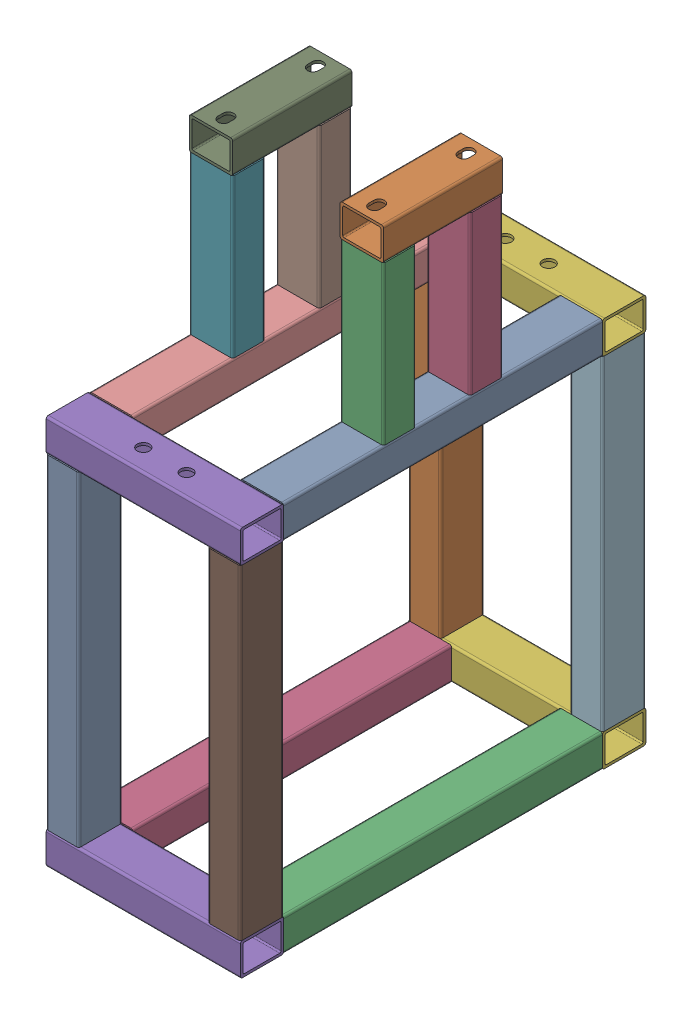
SolidWorks assembly Stand Assembly, configuration Default. Lengths in mm.
Overall size (227.56 680.52 475.21).
18 component instances, 6 part files, 51 mates.
Components (placement in the parent):
- Stand - Long Horizontal-1: Stand - Long Horizontal [6527K991] at (159.8005 177.7296 100.9544) size (50.8 38.1 373.61)
- Stand - Bearing Base-1: Stand - Bearing Base [6527K991] at (159.8005 401.049 217.9113) size (50.8 38.1 139.7)
- Stand - Bearing Leg-1: Stand - Bearing Leg [6527K991] at (159.8005 196.7796 338.5613) x (1 0 0) z (0 1 0) size (50.8 38.1 185.22)
- Stand - Bearing Leg-2: Stand - Bearing Leg [6527K991] at (159.8005 196.7796 236.9613) x (1 0 0) z (0 1 0) size (50.8 38.1 185.22)
- Stand - Short Horizontal - Holes-1: Stand - Short Horizontal - Holes [6527K991] at (-42.3632 177.7296 499.9681) x (0 0 -1) z (1 0 0) size (50.8 38.1 227.56)
- Stand - Short Horizontal - Holes-2: Stand - Short Horizontal - Holes [6527K991] at (185.2005 177.7296 75.5544) x (0 0 1) z (-1 0 0) size (50.8 38.1 227.56)
- Stand - Bearing Leg-3: Stand - Bearing Leg [6527K991] at (-16.9632 381.999 338.5613) x (1 0 0) z (0 -1 0) size (50.8 38.1 185.22)
- Stand - Bearing Leg-4: Stand - Bearing Leg [6527K991] at (-16.9632 381.999 236.9613) x (1 0 0) z (0 -1 0) size (50.8 38.1 185.22)
- Stand - Bearing Base-2: Stand - Bearing Base [6527K991] at (-16.9632 401.049 217.9113) size (50.8 38.1 139.7)
- Stand - Long Horizontal-2: Stand - Long Horizontal [6527K991] at (-16.9632 177.7296 100.9544) size (50.8 38.1 373.61)
- Stand - Legs-1: Stand - Legs [6527K991] at (166.1505 -222.3204 499.9681) x (0 0 -1) z (0 1 0) size (50.8 38.1 381)
- Stand - Legs-2: Stand - Legs [6527K991] at (166.1505 158.6796 75.5544) x (0 0 1) z (0 -1 0) size (50.8 38.1 381)
- Stand - Legs-3: Stand - Legs [6527K991] at (-23.3132 158.6796 499.9681) x (0 0 -1) z (0 -1 0) size (50.8 38.1 381)
- Stand - Legs-4: Stand - Legs [6527K991] at (-23.3132 -222.3204 75.5544) x (0 0 -1) z (0 1 0) size (50.8 38.1 381)
- Stand - Long Horizontal-3: Stand - Long Horizontal [6527K991] at (159.8005 -241.3704 100.9544) size (50.8 38.1 373.61)
- Stand - Long Horizontal-4: Stand - Long Horizontal [6527K991] at (-16.9632 -241.3704 100.9544) size (50.8 38.1 373.61)
- Stand - Short Horizontal-1: Stand - Short Horizontal [6527K991] at (185.2005 -241.3704 499.9681) x (0 0 1) z (-1 0 0) size (50.8 38.1 227.56)
- Stand - Short Horizontal-2: Stand - Short Horizontal [6527K991] at (-42.3632 -241.3704 75.5544) x (0 0 -1) z (1 0 0) size (50.8 38.1 227.56)
Mates (geometry in assembly coordinates):
- Coincident1: coincident anti-aligned: plane of Stand Assembly - 1.5 by 2 inch bearing horizontal-1 through (182.6605 381.999 357.6113) normal (0 -1 0); plane of Stand Assembly - 1.5 by 2 inch bearing vertical-2 through (182.6605 381.999 253.4713) normal (0 1 0)
- Coincident2: coincident anti-aligned: plane of Stand Assembly - 1.5 by 2 inch bearing horizontal-1 through (182.6605 381.999 357.6113) normal (0 -1 0); plane of Stand Assembly - 1.5 by 2 inch bearing vertical-1 through (182.6605 381.999 355.0713) normal (0 1 0)
- Coincident3: coincident aligned: line of Stand Assembly - 1.5 by 2 inch bearing horizontal-1 through (136.9405 381.999 357.6113) axis (1 0 0); line of Stand Assembly - 1.5 by 2 inch bearing vertical-1 through (136.9405 381.999 357.6113) axis (1 0 0)
- Coincident4: coincident anti-aligned: line of Stand Assembly - 1.5 by 2 inch bearing horizontal-1 through (136.9405 381.999 217.9113) axis (1 0 0); line of Stand Assembly - 1.5 by 2 inch bearing vertical-2 through (182.6605 381.999 217.9113) axis (-1 0 0)
- Coincident5: coincident aligned: plane of Stand Assembly - 1.5 by 2 inch bearing horizontal-1 through (185.2005 384.539 357.6113) normal (1 0 0); plane of Stand Assembly - 1.5 by 2 inch bearing vertical-2 through (185.2005 381.999 253.4713) normal (1 0 0)
- Coincident6: coincident aligned: plane of Stand Assembly - 1.5 by 2 inch bearing horizontal-1 through (185.2005 384.539 357.6113) normal (1 0 0); plane of Stand Assembly - 1.5 by 2 inch bearing vertical-1 through (185.2005 381.999 355.0713) normal (1 0 0)
- Coincident7: coincident anti-aligned: plane of Stand Assembly - 1.5 by 2 inch-1 through (182.6605 196.7796 474.5681) normal (0 1 0); plane of Stand Assembly - 1.5 by 2 inch bearing vertical-2 through (182.6605 196.7796 253.4713) normal (0 -1 0)
- Coincident8: coincident anti-aligned: line of Stand Assembly - 1.5 by 2 inch-1 through (136.9405 196.7796 217.9113) axis (1 0 0); line of Stand Assembly - 1.5 by 2 inch bearing vertical-2 through (182.6605 196.7796 217.9113) axis (-1 0 0)
- Coincident9: coincident aligned: plane of Stand Assembly - 1.5 by 2 inch-1 through (185.2005 161.2196 474.5681) normal (1 0 0); plane of Stand Assembly - 1.5 by 2 inch bearing vertical-2 through (185.2005 381.999 253.4713) normal (1 0 0)
- Coincident10: coincident anti-aligned: plane of Stand Assembly - 1.5 by 2 inch-1 through (182.6605 161.2196 100.9544) normal (0 0 -1); plane of Stand Assembly - 1.5 by 2 inch side piece-2 through (-42.3632 161.2196 100.9544) normal (0 0 1)
- Coincident11: coincident aligned: plane of Stand Assembly - 1.5 by 2 inch-1 through (185.2005 161.2196 474.5681) normal (1 0 0); plane of Stand Assembly - 1.5 by 2 inch side piece-2 through (185.2005 161.2196 98.4144) normal (1 0 0)
- Coincident12: coincident aligned: plane of Stand Assembly - 1.5 by 2 inch-1 through (182.6605 196.7796 474.5681) normal (0 1 0); plane of Stand Assembly - 1.5 by 2 inch side piece-2 through (-42.3632 196.7796 98.4144) normal (0 1 0)
- Coincident13: coincident anti-aligned: plane of Stand Assembly - 1.5 by 2 inch-1 through (182.6605 161.2196 474.5681) normal (0 0 1); plane of Stand Assembly - 1.5 by 2 inch side piece-1 through (185.2005 161.2196 474.5681) normal (0 0 -1)
- Coincident14: coincident aligned: plane of Stand Assembly - 1.5 by 2 inch-1 through (185.2005 161.2196 474.5681) normal (1 0 0); plane of Stand Assembly - 1.5 by 2 inch side piece-1 through (185.2005 161.2196 477.1081) normal (1 0 0)
- Coincident15: coincident aligned: plane of Stand Assembly - 1.5 by 2 inch-1 through (182.6605 196.7796 474.5681) normal (0 1 0); plane of Stand Assembly - 1.5 by 2 inch side piece-1 through (185.2005 196.7796 477.1081) normal (0 1 0)
- Coincident19: coincident anti-aligned: plane of Stand Assembly - 1.5 by 2 inch side piece-2 through (-42.3632 161.2196 100.9544) normal (0 0 1); plane of Stand Assembly - 1.5 by 2 inch-2 through (5.8968 161.2196 100.9544) normal (0 0 -1)
- Coincident20: coincident aligned: plane of Stand Assembly - 1.5 by 2 inch side piece-2 through (-42.3632 161.2196 98.4144) normal (-1 0 0); plane of Stand Assembly - 1.5 by 2 inch-2 through (-42.3632 161.2196 474.5681) normal (-1 0 0)
- Coincident21: coincident aligned: plane of Stand Assembly - 1.5 by 2 inch side piece-2 through (-42.3632 196.7796 98.4144) normal (0 1 0); plane of Stand Assembly - 1.5 by 2 inch-2 through (5.8968 196.7796 474.5681) normal (0 1 0)
- Coincident22: coincident anti-aligned: plane of Stand Assembly - 1.5 by 2 inch bearing vertical-4 through (5.8968 381.999 220.4513) normal (0 1 0); plane of Stand Assembly - 1.5 by 2 inch bearing horizontal-2 through (5.8968 381.999 357.6113) normal (0 -1 0)
- Coincident23: coincident anti-aligned: plane of Stand Assembly - 1.5 by 2 inch bearing vertical-3 through (5.8968 381.999 322.0513) normal (0 1 0); plane of Stand Assembly - 1.5 by 2 inch bearing horizontal-2 through (5.8968 381.999 357.6113) normal (0 -1 0)
- Coincident24: coincident aligned: line of Stand Assembly - 1.5 by 2 inch bearing vertical-4 through (-39.8232 381.999 217.9113) axis (1 0 0); line of Stand Assembly - 1.5 by 2 inch bearing horizontal-2 through (-39.8232 381.999 217.9113) axis (1 0 0)
- Coincident25: coincident aligned: plane of Stand Assembly - 1.5 by 2 inch bearing vertical-4 through (-42.3632 196.7796 220.4513) normal (-1 0 0); plane of Stand Assembly - 1.5 by 2 inch bearing horizontal-2 through (-42.3632 384.539 357.6113) normal (-1 0 0)
- Coincident26: coincident anti-aligned: line of Stand Assembly - 1.5 by 2 inch bearing vertical-3 through (5.8968 381.999 357.6113) axis (-1 0 0); line of Stand Assembly - 1.5 by 2 inch bearing horizontal-2 through (-39.8232 381.999 357.6113) axis (1 0 0)
- Coincident27: coincident aligned: plane of Stand Assembly - 1.5 by 2 inch bearing vertical-3 through (-42.3632 196.7796 322.0513) normal (-1 0 0); plane of Stand Assembly - 1.5 by 2 inch bearing horizontal-2 through (-42.3632 384.539 357.6113) normal (-1 0 0)
- Coincident28: coincident anti-aligned: plane of Stand Assembly - 1.5 by 2 inch bearing vertical-3 through (5.8968 196.7796 322.0513) normal (0 -1 0); plane of Stand Assembly - 1.5 by 2 inch-2 through (5.8968 196.7796 474.5681) normal (0 1 0)
- Coincident29: coincident aligned: plane of Stand Assembly - 1.5 by 2 inch bearing vertical-3 through (-42.3632 196.7796 322.0513) normal (-1 0 0); plane of Stand Assembly - 1.5 by 2 inch-2 through (-42.3632 161.2196 474.5681) normal (-1 0 0)
- Coincident30: coincident anti-aligned: line of Stand Assembly - 1.5 by 2 inch bearing vertical-3 through (5.8968 196.7796 357.6113) axis (-1 0 0); line of Stand Assembly - 1.5 by 2 inch-2 through (-39.8232 196.7796 357.6113) axis (1 0 0)
- Coincident33: coincident anti-aligned: plane of Stand Assembly - 1.5 by 2 inch side piece-2 through (-42.3632 158.6796 98.4144) normal (0 -1 0); plane of Stand Assembly - 1.5 by 2 inch legs-4 through (-6.8032 158.6796 52.6944) normal (0 1 0)
- Coincident34: coincident anti-aligned: plane of Stand Assembly - 1.5 by 2 inch side piece-2 through (-42.3632 158.6796 98.4144) normal (0 -1 0); plane of Stand Assembly - 1.5 by 2 inch legs-2 through (182.6605 158.6796 98.4144) normal (0 1 0)
- Coincident37: coincident aligned: plane of Stand Assembly - 1.5 by 2 inch side piece-2 through (185.2005 161.2196 98.4144) normal (1 0 0); plane of Stand Assembly - 1.5 by 2 inch legs-2 through (185.2005 -222.3204 98.4144) normal (1 0 0)
- Coincident38: coincident aligned: plane of Stand Assembly - 1.5 by 2 inch side piece-2 through (-42.3632 161.2196 50.1544) normal (0 0 -1); plane of Stand Assembly - 1.5 by 2 inch legs-2 through (182.6605 -222.3204 50.1544) normal (0 0 -1)
- Coincident39: coincident aligned: plane of Stand Assembly - 1.5 by 2 inch side piece-2 through (-42.3632 161.2196 98.4144) normal (-1 0 0); plane of Stand Assembly - 1.5 by 2 inch legs-4 through (-42.3632 158.6796 52.6944) normal (-1 0 0)
- Coincident40: coincident aligned: plane of Stand Assembly - 1.5 by 2 inch side piece-2 through (-42.3632 161.2196 50.1544) normal (0 0 -1); plane of Stand Assembly - 1.5 by 2 inch legs-4 through (-6.8032 158.6796 50.1544) normal (0 0 -1)
- Coincident41: coincident anti-aligned: plane of Stand Assembly - 1.5 by 2 inch side piece-1 through (185.2005 158.6796 477.1081) normal (0 -1 0); plane of Stand Assembly - 1.5 by 2 inch legs-3 through (-39.8232 158.6796 477.1081) normal (0 1 0)
- Coincident42: coincident aligned: plane of Stand Assembly - 1.5 by 2 inch side piece-1 through (-42.3632 161.2196 477.1081) normal (-1 0 0); plane of Stand Assembly - 1.5 by 2 inch legs-3 through (-42.3632 -222.3204 477.1081) normal (-1 0 0)
- Coincident43: coincident aligned: plane of Stand Assembly - 1.5 by 2 inch side piece-1 through (185.2005 161.2196 525.3681) normal (0 0 1); plane of Stand Assembly - 1.5 by 2 inch legs-3 through (-39.8232 -222.3204 525.3681) normal (0 0 1)
- Coincident44: coincident anti-aligned: plane of Stand Assembly - 1.5 by 2 inch side piece-1 through (185.2005 158.6796 477.1081) normal (0 -1 0); plane of Stand Assembly - 1.5 by 2 inch legs-1 through (182.6605 158.6796 477.1081) normal (0 1 0)
- Coincident45: coincident aligned: plane of Stand Assembly - 1.5 by 2 inch side piece-1 through (185.2005 161.2196 477.1081) normal (1 0 0); plane of Stand Assembly - 1.5 by 2 inch legs-1 through (185.2005 158.6796 477.1081) normal (1 0 0)
- Coincident46: coincident aligned: plane of Stand Assembly - 1.5 by 2 inch side piece-1 through (185.2005 161.2196 525.3681) normal (0 0 1); plane of Stand Assembly - 1.5 by 2 inch legs-1 through (182.6605 158.6796 525.3681) normal (0 0 1)
- Coincident47: coincident anti-aligned: plane of Stand Assembly - 1.5 by 2 inch legs-3 through (-39.8232 -222.3204 477.1081) normal (0 -1 0); plane of Stand Assembly - 1.5 by 2 inch side piece bottom-1 through (-42.3632 -222.3204 522.8281) normal (0 1 0)
- Coincident48: coincident aligned: plane of Stand Assembly - 1.5 by 2 inch legs-3 through (-39.8232 -222.3204 525.3681) normal (0 0 1); plane of Stand Assembly - 1.5 by 2 inch side piece bottom-1 through (-42.3632 -257.8804 525.3681) normal (0 0 1)
- Coincident49: coincident aligned: plane of Stand Assembly - 1.5 by 2 inch legs-3 through (-42.3632 -222.3204 477.1081) normal (-1 0 0); plane of Stand Assembly - 1.5 by 2 inch side piece bottom-1 through (-42.3632 -257.8804 522.8281) normal (-1 0 0)
- Coincident50: coincident anti-aligned: plane of Stand Assembly - 1.5 by 2 inch legs-2 through (182.6605 -222.3204 98.4144) normal (0 -1 0); plane of Stand Assembly - 1.5 by 2 inch side piece bottom-2 through (185.2005 -222.3204 52.6944) normal (0 1 0)
- Coincident51: coincident aligned: plane of Stand Assembly - 1.5 by 2 inch legs-4 through (-42.3632 158.6796 52.6944) normal (-1 0 0); plane of Stand Assembly - 1.5 by 2 inch side piece bottom-2 through (-42.3632 -257.8804 52.6944) normal (-1 0 0)
- Coincident52: coincident aligned: plane of Stand Assembly - 1.5 by 2 inch legs-4 through (-6.8032 158.6796 50.1544) normal (0 0 -1); plane of Stand Assembly - 1.5 by 2 inch side piece bottom-2 through (185.2005 -257.8804 50.1544) normal (0 0 -1)
- Coincident53: coincident aligned: plane of Stand Assembly - 1.5 by 2 inch-4 through (5.8968 -222.3204 474.5681) normal (0 1 0); plane of Stand Assembly - 1.5 by 2 inch side piece bottom-2 through (185.2005 -222.3204 52.6944) normal (0 1 0)
- Coincident54: coincident aligned: plane of Stand Assembly - 1.5 by 2 inch-4 through (-42.3632 -257.8804 474.5681) normal (-1 0 0); plane of Stand Assembly - 1.5 by 2 inch side piece bottom-2 through (-42.3632 -257.8804 52.6944) normal (-1 0 0)
- Coincident55: coincident anti-aligned: plane of Stand Assembly - 1.5 by 2 inch-4 through (5.8968 -257.8804 474.5681) normal (0 0 1); plane of Stand Assembly - 1.5 by 2 inch side piece bottom-1 through (-42.3632 -257.8804 474.5681) normal (0 0 -1)
- Coincident56: coincident aligned: plane of Stand Assembly - 1.5 by 2 inch-3 through (182.6605 -222.3204 474.5681) normal (0 1 0); plane of Stand Assembly - 1.5 by 2 inch side piece bottom-2 through (185.2005 -222.3204 52.6944) normal (0 1 0)
- Coincident57: coincident anti-aligned: plane of Stand Assembly - 1.5 by 2 inch-3 through (182.6605 -257.8804 474.5681) normal (0 0 1); plane of Stand Assembly - 1.5 by 2 inch side piece bottom-1 through (-42.3632 -257.8804 474.5681) normal (0 0 -1)
- Coincident58: coincident aligned: plane of Stand Assembly - 1.5 by 2 inch-3 through (185.2005 -257.8804 474.5681) normal (1 0 0); plane of Stand Assembly - 1.5 by 2 inch side piece bottom-1 through (185.2005 -257.8804 522.8281) normal (1 0 0)
